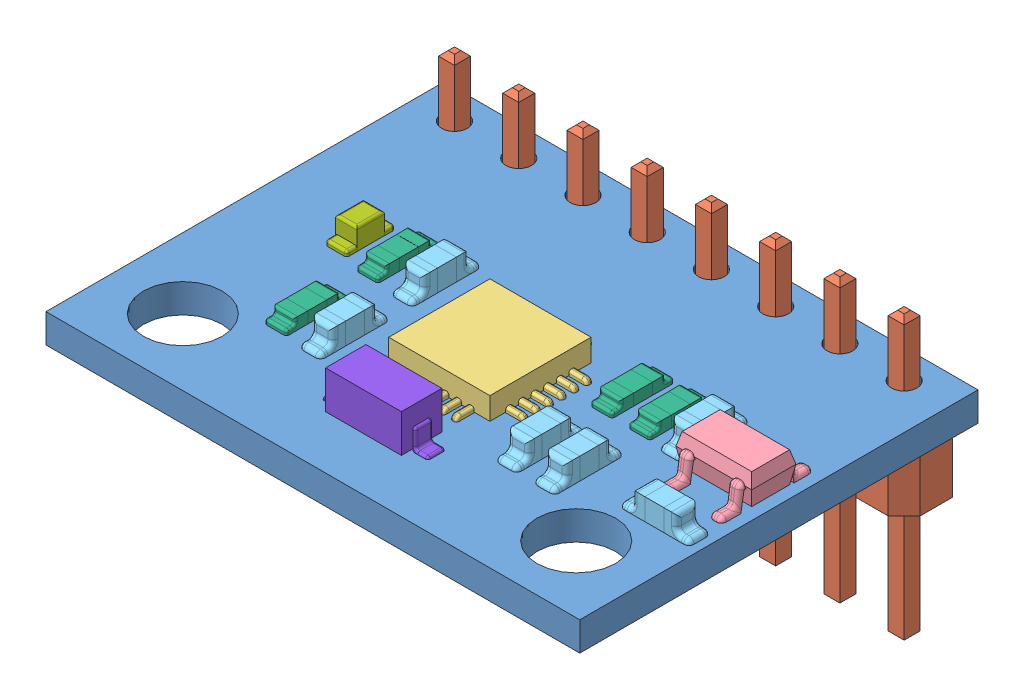
SolidWorks assembly MPU 6050 IMU, configuration Default. Lengths in mm.
Overall size (21.11 11.18 15.88).
23 component instances, 8 part files, 33 mates.
Components (placement in the parent):
- Base-1: Base [Default] at (7.2489 10.9584 16.5726) size (21.11 1.14 15.75)
- pin header-1: pin header [Default] at (16.0246 10.3869 9.8416) x (-1 0 0) z (0 0 1) size (2.54 11.18 2.54)
- pin header-2: pin header [Default] at (13.4846 10.3869 9.8416) x (-1 0 0) z (0 0 1) size (2.54 11.18 2.54)
- pin header-3: pin header [Default] at (10.9446 10.3869 9.8416) x (-1 0 0) z (0 0 1) size (2.54 11.18 2.54)
- pin header-4: pin header [Default] at (8.4046 10.3869 9.8416) x (-1 0 0) z (0 0 1) size (2.54 11.18 2.54)
- pin header-5: pin header [Default] at (5.8646 10.3869 9.8416) x (-1 0 0) z (0 0 1) size (2.54 11.18 2.54)
- pin header-6: pin header [Default] at (3.3246 10.3869 9.8416) x (-1 0 0) z (0 0 1) size (2.54 11.18 2.54)
- pin header-7: pin header [Default] at (0.7846 10.3869 9.8416) x (-1 0 0) z (0 0 1) size (2.54 11.18 2.54)
- pin header-8: pin header [Default] at (-1.7554 10.3869 9.8416) x (-1 0 0) z (0 0 1) size (2.54 11.18 2.54)
- sensor chip-1: sensor chip [Default] at (7.2489 11.5499 17.4466) size (5.4 0.9 5.4)
- S2NH chip-1: S2NH chip [Default] at (16.1026 12.3799 16.5726) size (3 1.35 3.65)
- Resistor small-3: Resistor small [Default] at (16.1026 11.5314 19.3726) size (2.75 0.99 1)
- Resistor small-4: Resistor small [Default] at (13.9776 11.5314 15.6976) x (0 0 -1) z (1 0 0) size (2.75 0.99 1)
- Resistor small black-3: Resistor small black [Default] at (12.6276 11.5299 15.6976) x (0 0 1) z (-1 0 0) size (2.45 0.6 1.02)
- Resistor small black-4: Resistor small black [Default] at (11.1276 11.5299 15.6976) x (0 0 1) z (-1 0 0) size (2.45 0.6 1.02)
- Resistor small-5: Resistor small [Default] at (12.6276 11.5314 19.3216) x (0 0 -1) z (1 0 0) size (2.75 0.99 1)
- Resistor small-6: Resistor small [Default] at (11.1276 11.5314 19.3216) x (0 0 -1) z (1 0 0) size (2.75 0.99 1)
- Resistor small-7: Resistor small [Default] at (3.3702 11.5314 19.3216) x (0 0 -1) z (1 0 0) size (2.75 0.99 1)
- Resistor small black-5: Resistor small black [Default] at (1.8702 11.5299 15.6972) x (0 0 -1) z (1 0 0) size (2.45 0.6 1.02)
- Resistor small-8: Resistor small [Default] at (3.3702 11.5314 15.6976) x (0 0 1) z (-1 0 0) size (2.75 0.99 1)
- Small LED-1: Small LED [Default] at (0.3652 11.5299 15.6976) size (0.85 0.84 1.9)
- Resistor small black-6: Resistor small black [Default] at (1.8702 11.5299 19.3216) x (0 0 1) z (-1 0 0) size (2.45 0.6 1.02)
- Resistor black-1: Resistor black [Default] at (7.2489 12.3799 21.6466) size (4.2 1.6 1.6)
Mates (geometry in assembly coordinates):
- Concentric1: concentric: cylinder of Base-1 through (16.0246 11.5299 9.8416) axis (0 -1 0) radius 0.508; point of pin header-1
- Coincident4: coincident anti-aligned: plane of Base-1 through (7.2489 10.3869 16.5726) normal (0 -1 0); plane of pin header-1 through (16.0246 10.3869 9.8416) normal (0 1 0)
- Parallel1: parallel aligned: plane of Base-1 through (17.8026 11.5299 24.4466) normal (1 0 0); plane of pin header-1 through (17.2946 7.8469 10.4766) normal (1 0 0)
- Coincident6: coincident anti-aligned: plane of Base-1 through (7.2489 11.5299 16.5726) normal (0 1 0); plane of sensor chip-1 through (7.2489 11.5299 17.4466) normal (0 -1 0)
- Coincident7: coincident aligned: plane of Base-1 through (7.2489 10.9584 16.5726) normal (1 0 0); plane of sensor chip-1 through (7.2489 11.5499 17.4466) normal (1 0 0)
- Distance1: distance = 5 mm aligned: plane of sensor chip-1 through (5.2489 12.4299 19.4466) normal (0 0 1); plane of Base-1 through (-3.3048 11.5299 24.4466) normal (0 0 1)
- Coincident8: coincident anti-aligned: plane of Base-1 through (7.2489 11.5299 16.5726) normal (0 1 0); plane of S2NH chip-1 through (16.1026 11.5299 16.5726) normal (0 -1 0)
- Coincident9: coincident aligned: plane of Base-1 through (7.2489 10.9584 16.5726) normal (0 0 1); plane of S2NH chip-1 through (16.1026 12.3799 16.5726) normal (0 0 1)
- Distance2: distance = 0.2 mm: line of S2NH chip-1 through (17.6026 12.3799 17.4476) axis (0 0 -1); plane of Base-1 through (17.8026 11.5299 24.4466) normal (1 0 0)
- Coincident19: coincident anti-aligned: plane of Base-1 through (7.2489 11.5299 16.5726) normal (0 1 0); plane of Resistor small-3 through (16.9776 11.5299 19.8026) normal (0 -1 0)
- Coincident20: coincident aligned: plane of S2NH chip-1 through (16.1026 12.3799 16.5726) normal (1 0 0); plane of Resistor small-3 through (16.1026 11.5314 19.3726) normal (1 0 0)
- Distance5: distance = 1.5 mm: line of S2NH chip-1 through (15.3258 12.3799 17.4476) axis (1 0 0); plane of Resistor small-3 through (16.4776 11.5314 18.9476) normal (0 0 -1)
- Coincident22: coincident anti-aligned: plane of Base-1 through (7.2489 11.5299 16.5726) normal (0 1 0); plane of Resistor small-4 through (14.4076 11.5299 14.8226) normal (0 -1 0)
- Coincident24: coincident: line of S2NH chip-1 through (16.8794 12.3799 15.6976) axis (-1 0 0); plane of Resistor small-4 through (13.9776 11.5314 15.6976) normal (0 0 -1)
- Distance6: distance = 0.2 mm: plane of Resistor small-4 through (14.4026 11.5314 15.3226) normal (1 0 0); line of S2NH chip-1 through (14.6026 12.3799 15.6976) axis (0 0 1)
- Coincident26: coincident anti-aligned: plane of Base-1 through (7.2489 11.5299 16.5726) normal (0 1 0); plane of Resistor small black-3 through (12.2026 11.5299 16.0726) normal (0 -1 0)
- Coincident28: coincident anti-aligned: plane of Resistor small-4 through (13.9776 11.5314 15.6976) normal (0 0 -1); plane of Resistor small black-3 through (12.6276 11.5299 15.6976) normal (0 0 1)
- Distance7: distance = 0.5 mm anti-aligned: plane of Resistor small-4 through (13.5526 11.5314 15.3226) normal (-1 0 0); plane of Resistor small black-3 through (13.0526 11.5299 16.0726) normal (1 0 0)
- Coincident30: coincident anti-aligned: plane of Base-1 through (7.2489 11.5299 16.5726) normal (0 1 0); plane of Resistor small-5 through (13.0576 11.5299 18.4466) normal (0 -1 0)
- Coincident31: coincident anti-aligned: plane of Resistor small black-3 through (12.6276 11.5299 15.6976) normal (-1 0 0); plane of Resistor small-5 through (12.6276 11.5314 19.3216) normal (1 0 0)
- Distance8: distance = 4.25 mm aligned: plane of Resistor small-5 through (12.6276 11.5314 20.1966) normal (0 0 1); plane of Base-1 through (-3.3048 11.5299 24.4466) normal (0 0 1)
- Coincident33: coincident anti-aligned: plane of Base-1 through (7.2489 11.5299 16.5726) normal (0 1 0); plane of Resistor small-8 through (2.9402 11.5299 14.8226) normal (0 -1 0)
- Coincident34: coincident anti-aligned: plane of Resistor small-7 through (3.3702 11.5314 19.3216) normal (1 0 0); plane of Resistor small-8 through (3.3702 11.5314 15.6976) normal (-1 0 0)
- Coincident36: coincident: line of S2NH chip-1 through (15.8794 12.3799 15.6976) axis (-1 0 0); plane of Resistor small-8 through (3.3702 11.5314 15.6976) normal (0 0 1)
- Coincident37: coincident anti-aligned: plane of Base-1 through (7.2489 11.5299 16.5726) normal (0 1 0); plane of Small LED-1 through (0.3652 11.5299 15.6976) normal (0 -1 0)
- Coincident38: coincident: line of S2NH chip-1 through (15.8794 12.3799 15.6976) axis (-1 0 0); plane of Small LED-1 through (0.3652 11.5299 15.6976) normal (0 0 1)
- Distance9: distance = 1.5 mm aligned: plane of Small LED-1 through (-0.0548 12.3699 16.2476) normal (-1 0 0); plane of Resistor small black-5 through (1.4452 11.5299 15.3222) normal (-1 0 0)
- Coincident40: coincident anti-aligned: plane of Base-1 through (7.2489 11.5299 16.5726) normal (0 1 0); plane of Resistor small black-6 through (1.4452 11.5299 19.6966) normal (0 -1 0)
- Coincident41: coincident anti-aligned: plane of Resistor small black-5 through (1.8702 11.5299 15.6972) normal (1 0 0); plane of Resistor small black-6 through (1.8702 11.5299 19.3216) normal (-1 0 0)
- Coincident42: coincident anti-aligned: plane of Resistor small-7 through (3.3702 11.5314 19.3216) normal (0 0 -1); plane of Resistor small black-6 through (1.8702 11.5299 19.3216) normal (0 0 1)
- Coincident43: coincident anti-aligned: plane of Base-1 through (7.2489 11.5299 16.5726) normal (0 1 0); plane of Resistor black-1 through (5.6489 11.5299 21.9966) normal (0 -1 0)
- Coincident44: coincident aligned: plane of Base-1 through (7.2489 10.9584 16.5726) normal (1 0 0); plane of Resistor black-1 through (7.2489 12.3799 21.6466) normal (1 0 0)
- Distance10: distance = 2 mm aligned: plane of Resistor black-1 through (5.7489 13.1299 22.4466) normal (0 0 1); plane of Base-1 through (-3.3048 11.5299 24.4466) normal (0 0 1)
